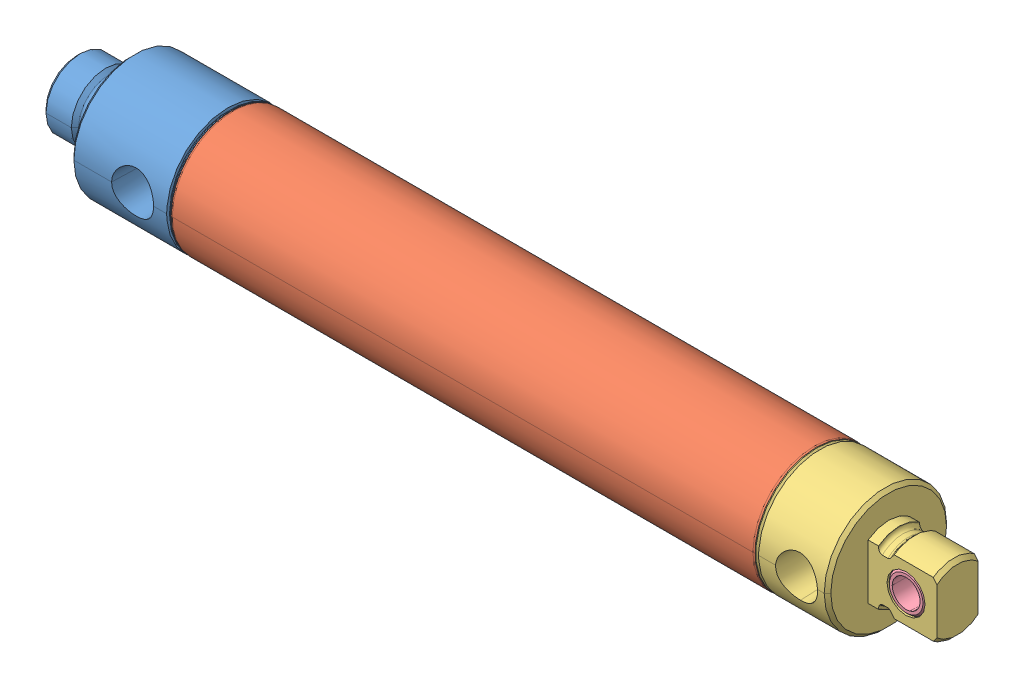
SolidWorks assembly SR_094_DPY, configuration Default. Lengths in mm.
Overall size (203.1 28.27 28.33).
4 component instances, 4 part files, 0 mates.
Components (placement in the parent):
- _09R000_0_rod_guide_4-1: _09R000_0_rod_guide_4 [Default] at origin size (41.28 28.27 28.27)
- _09R_5_31350SR_6-1: _09R_5_31350SR_6 [Default] at (35.6235 0 0) size (136.32 28.27 28.27)
- _09P0Y000_rear_head_8-1: _09P0Y000_rear_head_8 [Default] at (164.9984 0 0) size (38.1 28.22 28.3)
- _D_3543_10-1: _D_3543_10 [Default] at (195.961 0 0) x (1 0 0) z (0 0 -1) size (8.78 8.78 9.4)
